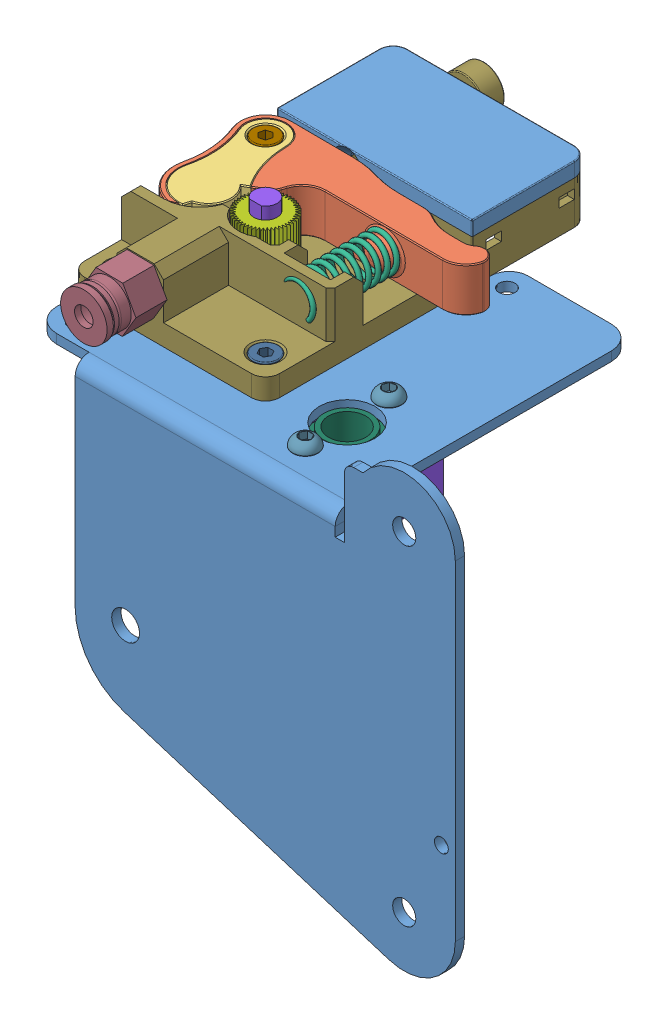
SolidWorks assembly 挤出器固定板右装配, configuration 默认. Lengths in mm.
Overall size (103.87 96.5 86.15).
25 component instances, 19 part files, 50 mates.
Components (placement in the parent):
- 一体挤出器固定板右_钣金-1: 一体挤出器固定板右_钣金 [默认<按加工>] at (-55.4694 -7.0201 25.25) size (103.87 93 64.5)
- 手柄装配-1: 手柄装配 [Default] at (-45.182 -16.434 -29.5723) x (0.999984 0 0.005666) z (0 1 0) size (52.63 28.87 49.74)
  - 右挤出器手柄-1: 右挤出器手柄 [默认] at (-58.5845 -22.2423 40.7539) size (52.63 28.37 9.5)
  - 右挤出器盖板-1: 右挤出器盖板 [默认] at (-58.6245 -22.2423 41.2539) size (12.69 26.44 5.5)
  - U型轴承-1: U型轴承 [默认] at (-70.8245 -22.2423 48.5056) x (-0.923728 0.383049 0) z (0 0 1) size (12 12 4)
  - M3_8圆柱-1: M3_8圆柱 [默认] at (-70.8245 -22.2423 46.5056) x (-0.923728 0.383049 0) z (0 0 1) size (3 3 8)
- 1_8_25弹簧-1: 1_8_25弹簧 [Default] at (-89.8435 34.2199 -4.8893) x (0.986352 0.16465 0) z (-0.16465 0.986352 0) size (8.42 22 8.42)
- 电机轴齿轮-1: 电机轴齿轮 [默认] at (-103.8435 28.9799 -7.75) x (0.005666 0 -0.999984) z (0 1 0) size (10.88 10.88 11.4)
- 42型步进电机-1: 42型步进电机 [Default] at (-103.8435 6.2299 -7.75) x (-1 0 0) z (0 0 -1) size (42.3 53.75 48.3)
- 内六角沉头螺栓M3_20-1: 内六角沉头螺栓M3_20 [内六角沉头螺栓M3_20] at (-119.3435 38.9799 -23.25) x (0.962664 0 -0.270699) z (0.270699 0 0.962664) size (5.6 20 5.6)
- 内六角沉头M3_10-4: 内六角沉头M3_10 [内六角沉头M3_10] at (-88.3435 29.4799 -23.25) x (-0.213376 0 -0.97697) z (0.97697 0 -0.213376) size (5.6 10 5.6)
- 机米M3-2: 机米M3 [机米M3] at (-98.3436 31.7799 -7.7189) x (-0.999984 0 -0.005666) z (0 1 0) size (3 3 3)
- 远端挤出器料丝检测一体底座-1: 远端挤出器料丝检测一体底座 [默认] at (-103.8435 24.9799 -7.75) x (1 0 0) z (0 1 0) size (42 74 14.5)
- 内六角沉头M3_10-1: 内六角沉头M3_10 [内六角沉头M3_10] at (-88.3435 29.4799 7.75) size (5.6 10 5.6)
- 内六角沉头M3_10-3: 内六角沉头M3_10 [内六角沉头M3_10] at (-119.3435 29.4799 7.75) size (5.6 10 5.6)
- 气动接头4-M6-1: 气动接头4-M6 [气动接头4-M8] at (-109.8135 34.2199 6.55) size (11.55 10.07 18.75)
- 圆头内六角M3_8-3: 圆头内六角M3_8 [圆头内六角M3_8] at (-70.9735 24.9799 16.55) size (5.49 10 5.49)
- 丝杆螺母-M24-1: 丝杆螺母-M24 [Default] at (-70.9735 22.1799 7.55) x (-1 0 0) z (0 0 1) size (12.8 10.7 24)
- 圆头内六角M3_8-2: 圆头内六角M3_8 [圆头内六角M3_8] at (-70.9735 24.9799 -1.45) x (0.982082 0 -0.188455) z (0.188455 0 0.982082) size (5.49 10 5.49)
- 弹性垫片M3-1: 弹性垫片M3 [弹性垫片M3] at (-70.9735 22.9799 -1.45) x (0 0 1) z (0 1 0) size (5 5 0.8)
- 弹性垫片M3-2: 弹性垫片M3 [弹性垫片M3] at (-70.9735 22.9799 16.55) x (0.188455 0 0.982082) z (0 1 0) size (5 5 0.8)
- 料丝检测开关-新-1: 料丝检测开关-新 [默认] at (-103.2135 31.6199 -43.9) x (0 0 -1) z (1 0 0) size (20 15.45 17.4)
- M2.2x6自攻螺钉-1: M2.2x6自攻螺钉 [默认] at (-103.2135 34.2199 -51.4) x (0 -1 0) z (0 0 1) size (7.62 3.8 3.8)
- M2.2x6自攻螺钉-2: M2.2x6自攻螺钉 [默认] at (-103.2135 34.2199 -36.4) x (0 -1 0) z (0.188455 0 0.982082) size (7.62 3.8 3.8)
- 远端挤出器料丝检测一体上盖-1: 远端挤出器料丝检测一体上盖 [默认] at (-103.8435 37.3199 -43.75) x (1 0 0) z (0 0 -1) size (42 6.45 25)
Mates (geometry in assembly coordinates):
- 重合42: coincident aligned: plane of 手柄装配-1/右挤出器盖板-1 through (-116.1314 38.9799 -7.7316) normal (0 1 0); plane of 内六角沉头螺栓M3_20-1 through (-116.4555 38.9799 -24.0621) normal (0 1 0)
- 同心62: concentric aligned: cylinder of 内六角沉头螺栓M3_20-1 through (-119.3435 18.9799 -23.25) axis (0 1 0) radius 1.5; cylinder of 手柄装配-1/右挤出器盖板-1 through (-119.3435 38.9799 -23.25) axis (0 1 0) radius 1.6
- 同心42: concentric aligned: cylinder of 电机轴齿轮-1 through (-103.8435 40.3799 -7.75) axis (0 -1 0) radius 2.5; cylinder of 42型步进电机-1 through (-103.8435 42.9799 -7.75) axis (0 -1 0) radius 2.5
- 距离1: distance = 4 mm anti-aligned: plane of 电机轴齿轮-1 through (-103.8435 28.9799 -7.75) normal (0 -1 0); plane of 42型步进电机-1 through (-103.8435 24.9799 -7.75) normal (0 1 0)
- 同心61: concentric anti-aligned: cylinder of 电机轴齿轮-1 through (-97.9858 31.7799 -7.7168) axis (-0.999984 0 -0.005666) radius 1.2; cylinder of 机米M3-2 through (-83.5697 31.7799 -7.6352) axis (0.999984 0 0.005666) radius 1.5
- 相切1: tangent anti-aligned: cylinder of 电机轴齿轮-1 through (-103.8435 40.3799 -7.75) axis (0 -1 0) radius 2.5; plane of 机米M3-2 through (-101.3436 31.7799 -7.7359) normal (-0.999984 0 -0.005666)
- 重合45: coincident anti-aligned: plane of 一体挤出器固定板右_钣金-1 through (-60.8435 22.9799 -34.25) normal (0 -1 0); plane of 42型步进电机-1 through (-82.6935 22.9799 13.4) normal (0 1 0)
- 同心67: concentric aligned: cylinder of 远端挤出器料丝检测一体底座-1 through (-88.3435 29.4799 7.75) axis (0 -1 0) radius 1.5; cylinder of 一体挤出器固定板右_钣金-1 through (-88.3435 24.9799 7.75) axis (0 -1 0) radius 1.6
- 重合46: coincident anti-aligned: plane of 一体挤出器固定板右_钣金-1 through (-60.8435 24.9799 -34.25) normal (0 1 0); plane of 远端挤出器料丝检测一体底座-1 through (-85.8435 24.9799 10.25) normal (0 -1 0)
- 重合47: coincident aligned: plane of 内六角沉头M3_10-4 through (-88.9836 29.4799 -26.1809) normal (0 1 0); plane of 远端挤出器料丝检测一体底座-1 through (-85.8435 29.4799 10.25) normal (0 1 0)
- 重合48: coincident anti-aligned: plane of 手柄装配-1/右挤出器手柄-1 through (-116.1314 29.4799 -7.7316) normal (0 -1 0); plane of 远端挤出器料丝检测一体底座-1 through (-85.8435 29.4799 10.25) normal (0 1 0)
- 平行3: parallel aligned: line of 手柄装配-1/右挤出器手柄-1 through (-109.8435 34.2299 -44.8104) axis (0 0 1); cylinder of 远端挤出器料丝检测一体底座-1 through (-109.8135 34.2199 17.4848) axis (0 0 1) radius 1.1
- 同心72: concentric anti-aligned: line of 1_8_25弹簧-1 through (-89.8435 34.2199 12.683) axis (0 0 -1); cylinder of 远端挤出器料丝检测一体底座-1 through (-89.8435 34.2199 15.6322) axis (0 0 1) radius 3
- 锁定2: lock: unknown of 1_8_25弹簧-1; unknown of 远端挤出器料丝检测一体底座-1
- 同心73: concentric aligned: cylinder of 远端挤出器料丝检测一体底座-1 through (-88.3435 26.9799 -23.25) axis (0 -1 0) radius 3; cylinder of 一体挤出器固定板右_钣金-1 through (-88.3435 24.9799 -23.25) axis (0 -1 0) radius 1.6
- 同心74: concentric anti-aligned: cylinder of 远端挤出器料丝检测一体底座-1 through (-119.3435 29.4799 7.75) axis (0 -1 0) radius 1.5; cylinder of 内六角沉头M3_10-3 through (-119.3435 19.4799 7.75) axis (0 1 0) radius 1.5
- 重合49: coincident aligned: plane of 远端挤出器料丝检测一体底座-1 through (-85.8435 29.4799 10.25) normal (0 1 0); plane of 内六角沉头M3_10-3 through (-116.3435 29.4799 7.75) normal (0 1 0)
- 同心75: concentric anti-aligned: cylinder of 远端挤出器料丝检测一体底座-1 through (-88.3435 29.4799 7.75) axis (0 -1 0) radius 1.5; cylinder of 内六角沉头M3_10-1 through (-88.3435 19.4799 7.75) axis (0 1 0) radius 1.5
- 重合50: coincident aligned: plane of 远端挤出器料丝检测一体底座-1 through (-85.8435 29.4799 10.25) normal (0 1 0); plane of 内六角沉头M3_10-1 through (-85.3435 29.4799 7.75) normal (0 1 0)
- 重合51: coincident anti-aligned: plane of 远端挤出器料丝检测一体底座-1 through (-121.8435 29.4799 13.25) normal (0 0 1); plane of 气动接头4-M6-1 through (-109.8135 34.2199 13.25) normal (0 0 -1)
- 同心76: concentric anti-aligned: cylinder of 远端挤出器料丝检测一体底座-1 through (-109.8135 34.2199 13.25) axis (0 0 1) radius 2.5; cylinder of 气动接头4-M6-1 through (-109.8135 34.2199 13.25) axis (0 0 -1) radius 3
- 同心77: concentric anti-aligned: cylinder of 丝杆螺母-M24-1 through (-70.9735 13.4789 7.55) axis (0 1 0) radius 4; cylinder of 一体挤出器固定板右_钣金-1 through (-70.9735 24.9799 7.55) axis (0 -1 0) radius 6
- 平行4: parallel anti-aligned: plane of 一体挤出器固定板右_钣金-1 through (-55.8435 24.9799 23.25) normal (1 0 0); plane of 丝杆螺母-M24-1 through (-77.3735 18.4799 -2.6009) normal (-1 0 0)
- 同心78: concentric aligned: cylinder of 圆头内六角M3_8-3 through (-70.9735 16.9799 16.55) axis (0 1 0) radius 1.5; cylinder of 丝杆螺母-M24-1 through (-70.9735 22.1799 16.55) axis (0 1 0) radius 1.25
- 重合53: coincident anti-aligned: plane of 一体挤出器固定板右_钣金-1 through (-60.8435 24.9799 -34.25) normal (0 1 0); plane of 圆头内六角M3_8-3 through (-70.9735 24.9799 16.55) normal (0 -1 0)
- 同心81: concentric aligned: cylinder of 圆头内六角M3_8-2 through (-70.9735 16.9799 -1.45) axis (0 1 0) radius 1.5; cylinder of 丝杆螺母-M24-1 through (-70.9735 22.1799 -1.45) axis (0 1 0) radius 1.25
- 重合56: coincident anti-aligned: plane of 一体挤出器固定板右_钣金-1 through (-60.8435 24.9799 -34.25) normal (0 1 0); plane of 圆头内六角M3_8-2 through (-70.9735 24.9799 -1.45) normal (0 -1 0)
- 同心82: concentric anti-aligned: cylinder of 内六角沉头螺栓M3_20-1 through (-119.3435 18.9799 -23.25) axis (0 1 0) radius 1.5; cylinder of 远端挤出器料丝检测一体底座-1 through (-119.3435 29.4799 -23.25) axis (0 -1 0) radius 1.5
- 同心83: concentric anti-aligned: cylinder of 内六角沉头M3_10-4 through (-88.3435 19.4799 -23.25) axis (0 1 0) radius 1.5; cylinder of 远端挤出器料丝检测一体底座-1 through (-88.3435 26.9799 -23.25) axis (0 -1 0) radius 3
- 同心84: concentric aligned: cylinder of 一体挤出器固定板右_钣金-1 through (-103.8435 24.9799 -7.75) axis (0 -1 0) radius 11.5; cylinder of 42型步进电机-1 through (-103.8435 24.9799 -7.75) axis (0 -1 0) radius 11
- 同心85: concentric anti-aligned: cylinder of 一体挤出器固定板右_钣金-1 through (-88.3435 24.9799 -23.25) axis (0 -1 0) radius 1.6; cylinder of 42型步进电机-1 through (-88.3435 16.9799 -23.25) axis (0 1 0) radius 1.5
- 重合571: coincident anti-aligned: plane of 弹性垫片M3-1 through (-70.9735 22.9799 -1.45) normal (0 1 0); plane of 一体挤出器固定板右_钣金-1 through (-60.8435 22.9799 -34.25) normal (0 -1 0)
- 同心86: concentric aligned: cylinder of 丝杆螺母-M24-1 through (-70.9735 22.1799 -1.45) axis (0 1 0) radius 1.25; cylinder of 弹性垫片M3-1 through (-70.9735 22.1799 -1.45) axis (0 1 0) radius 2.5
- 重合58: coincident anti-aligned: plane of 一体挤出器固定板右_钣金-1 through (-60.8435 22.9799 -34.25) normal (0 -1 0); plane of 弹性垫片M3-2 through (-70.9735 22.9799 16.55) normal (0 1 0)
- 同心87: concentric aligned: cylinder of 丝杆螺母-M24-1 through (-70.9735 22.1799 16.55) axis (0 1 0) radius 1.25; cylinder of 弹性垫片M3-2 through (-70.9735 22.1799 16.55) axis (0 1 0) radius 2.5
- 重合59: coincident anti-aligned: plane of 丝杆螺母-M24-1 through (-70.9735 22.1799 7.55) normal (0 1 0); plane of 弹性垫片M3-2 through (-70.9735 22.1799 16.55) normal (0 -1 0)
- 重合572: coincident anti-aligned: plane of 远端挤出器料丝检测一体底座-1 through (-103.8435 31.6199 -7.75) normal (0 1 0); plane of 料丝检测开关-新-1 through (-103.2135 31.6199 -43.9) normal (0 -1 0)
- 同心88: concentric aligned: cylinder of 远端挤出器料丝检测一体底座-1 through (-103.2135 39.481 -51.4) axis (0 -1 0) radius 0.85; cylinder of 料丝检测开关-新-1 through (-103.2135 32.6199 -51.4) axis (0 -1 0) radius 1.25
- 同心89: concentric aligned: cylinder of 远端挤出器料丝检测一体底座-1 through (-103.2135 39.481 -36.4) axis (0 -1 0) radius 0.85; cylinder of 料丝检测开关-新-1 through (-103.2135 32.6199 -36.4) axis (0 -1 0) radius 1.25
- 重合573: coincident anti-aligned: plane of 料丝检测开关-新-1 through (-103.2135 32.6199 -43.9) normal (0 1 0); plane of M2.2x6自攻螺钉-1 through (-101.3135 32.6199 -51.4) normal (0 -1 0)
- 同心90: concentric anti-aligned: cylinder of 远端挤出器料丝检测一体底座-1 through (-103.2135 39.481 -51.4) axis (0 -1 0) radius 0.85; cylinder of M2.2x6自攻螺钉-1 through (-103.2135 41.1965 -51.4) axis (0 1 0) radius 1.1
- 重合574: coincident anti-aligned: plane of 料丝检测开关-新-1 through (-103.2135 32.6199 -43.9) normal (0 1 0); plane of M2.2x6自攻螺钉-2 through (-101.3476 32.6199 -36.7581) normal (0 -1 0)
- 同心91: concentric anti-aligned: cylinder of 远端挤出器料丝检测一体底座-1 through (-103.2135 39.481 -36.4) axis (0 -1 0) radius 0.85; cylinder of M2.2x6自攻螺钉-2 through (-103.2135 41.1965 -36.4) axis (0 1 0) radius 1.1
- 重合575: coincident anti-aligned: plane of 远端挤出器料丝检测一体底座-1 through (-85.8435 34.2199 -53.25) normal (0 1 0); plane of 远端挤出器料丝检测一体上盖-1 through (-103.8435 34.2199 -43.75) normal (0 -1 0)
- 重合576: coincident aligned: plane of 远端挤出器料丝检测一体底座-1 through (-124.8435 34.2199 -31.25) normal (0 0 1); plane of 远端挤出器料丝检测一体上盖-1 through (-124.8435 34.2199 -31.25) normal (0 0 1)
- 重合577: coincident aligned: plane of 远端挤出器料丝检测一体底座-1 through (-82.8435 29.4799 -53.25) normal (1 0 0); plane of 远端挤出器料丝检测一体上盖-1 through (-82.8435 34.2199 -31.25) normal (1 0 0)
- 重合578: coincident anti-aligned: plane of 远端挤出器料丝检测一体上盖-1 through (-87.8435 35.7199 -43.75) normal (0 1 0); plane of ? through (-85.0935 35.7199 -43.75) normal (0 -1 0)
- 同心92: concentric aligned: cylinder of 远端挤出器料丝检测一体底座-1 through (-87.8435 24.9789 -43.75) axis (0 1 0) radius 1.175; cylinder of ? through (-87.8435 45.0965 -43.75) axis (0 1 0) radius 1.45
- 重合579: coincident anti-aligned: plane of 远端挤出器料丝检测一体上盖-1 through (-119.8435 35.7199 -43.75) normal (0 1 0); plane of ? through (-117.1428 35.7199 -44.2683) normal (0 -1 0)
- 同心93: concentric aligned: cylinder of 远端挤出器料丝检测一体上盖-1 through (-119.8435 37.7199 -43.75) axis (0 1 0) radius 1.5; cylinder of ? through (-119.8435 45.0965 -43.75) axis (0 1 0) radius 1.45
